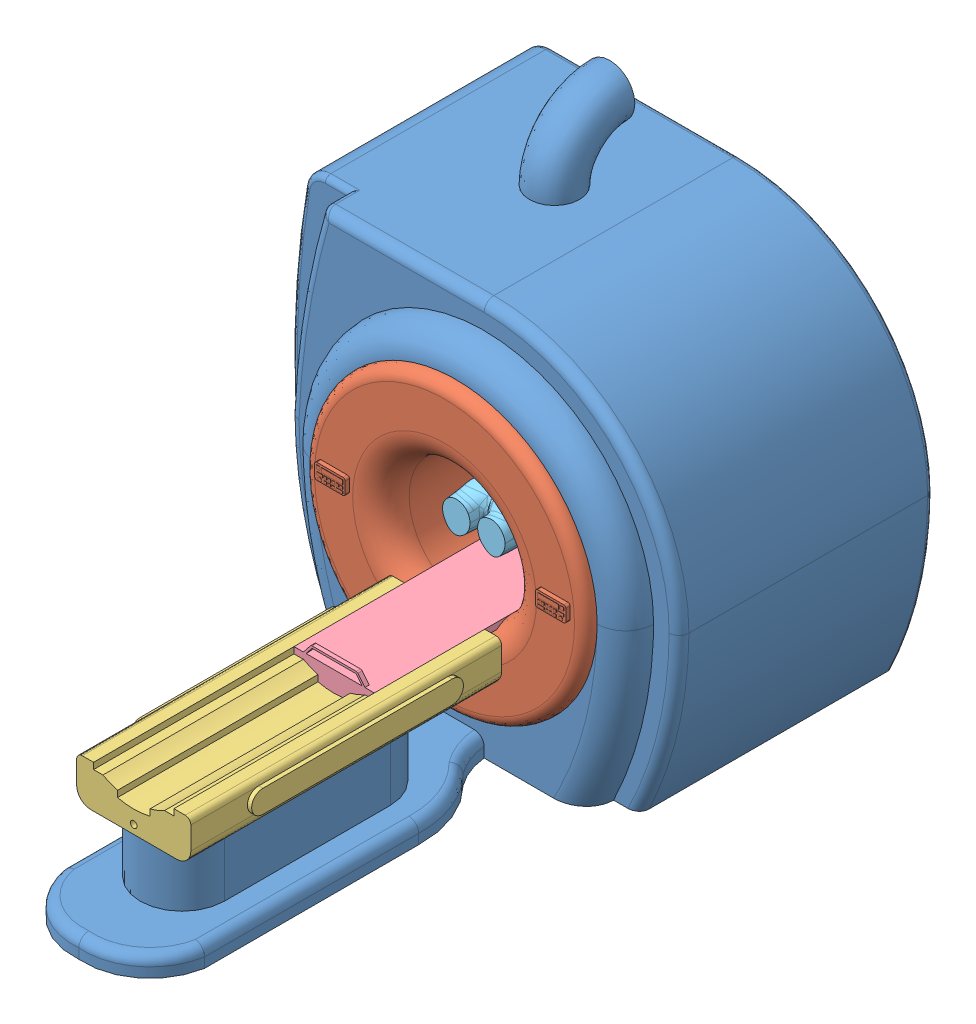
SolidWorks assembly Assem1, configuration Default. Lengths in mm.
Overall size (2298.25 2472.53 3646.55).
32 component instances, 9 part files, 5 mates.
Components (placement in the parent):
- MRI scanner-1: MRI scanner [Default] at (661.8458 1614.7998 1684.1916) size (2298.25 2472.53 3646.55)
  - Base Frame-1: Base Frame [Default] at (215.0742 187.8159 122.1083) size (2298.25 2472.53 3646.55)
  - Center Part-1: Center Part [Default] at (370.4063 184.7421 93.4615) size (1560 1560 1647.36)
  - Bed Base-1: Bed Base [Default] at (341.9747 -206.076 1751.6096) size (677.53 234 1716)
- Moving Bed-1: Moving Bed [Default] at (1003.8204 1488.5238 2331.8957) size (443.53 166.13 1716)
- BODYdetector-1: BODYdetector [Default] at (1333.5862 1343.5533 2745.5924) x (-1 0 0) z (0 0 -1) size (637.83 457.49 817.55)
  - woman body-1: woman body [Default] at (325.4407 484.4544 221.086) size (637.83 301.02 817.55)
  - Detector_posterial-1: Detector_posterial [Default] at (222.7152 725.2068 938.4124) x (1 0 0) z (0 0 -1) size (482.7 103.57 200)
    - 1Detector-1: 1Detector [Default] at (83.9721 85.3161 150.6758) size (71 32 200)
    - 1Detector-2: 1Detector [Default] at (152.9721 85.3161 150.6758) size (71 32 200)
    - 1Detector-3: 1Detector [Default] at (14.9721 85.3161 150.6758) size (71 32 200)
    - 1Detector-4: 1Detector [Default] at (-63.2042 99.8052 150.6758) x (0.93358 -0.358368 0) z (0 0 1) size (71 32 200)
    - 1Detector-5: 1Detector [Default] at (231.1484 99.8052 150.6758) x (0.93358 0.358368 0) z (0 0 1) size (71 32 200)
    - 1Detector_3modules-1: 1Detector_3modules [Default] at (-130.9957 141.3479 175.6758) x (0.743145 -0.669131 0) z (0 0 1) size (71 32 150)
    - 1Detector_3modules-2: 1Detector_3modules [Default] at (298.9398 141.3479 175.6758) x (0.743145 0.669131 0) z (0 0 1) size (71 32 150)
  - Detector1n2_2-1: Detector1n2_2 [Default] at (262.1834 410.9569 572.8392) x (1 0 0) z (0 -1 0) size (495.24 340.33 230.2)
    - top_bottomDetector2-1: top_bottomDetector2 [Default] at (5.3043 60.2155 74.3483) size (141 32 149.74)
    - CshapedDetector2-1: CshapedDetector2 [Default] at (104.3454 -76.5763 -85.899) x (0.951057 0.309017 0) z (0 0 1) size (177.89 270.84 200)
      - 1Detector-2: 1Detector [Default] at (173.0714 153.2337 184.2598) x (0.809017 0.587785 0) z (0 0 1) size (71 32 200)
      - 1Detector-4: 1Detector [Default] at (223.2683 222.3237 184.2598) x (0.309017 0.951057 0) z (0 0 1) size (71 32 200)
      - 1Detector-5: 1Detector [Default] at (223.2683 307.7237 184.2598) x (-0.309017 0.951057 0) z (0 0 1) size (71 32 200)
      - 1Detector_3modules-1: 1Detector_3modules [Default] at (91.8512 126.8436 209.2598) size (71 32 150)
      - 1Detector_3modules-2: 1Detector_3modules [Default] at (173.0714 376.8138 209.2598) x (-0.809017 0.587785 0) z (0 0 1) size (71 32 150)
    - CshapedDetector2-2: CshapedDetector2 [Default] at (-23.7368 484.2959 -85.899) x (-0.951057 -0.309017 0) z (0 0 1) size (177.89 270.84 200)
      - 1Detector-2: 1Detector [Default] at (173.0714 153.2337 184.2598) x (0.809017 0.587785 0) z (0 0 1) size (71 32 200)
      - 1Detector-4: 1Detector [Default] at (223.2683 222.3237 184.2598) x (0.309017 0.951057 0) z (0 0 1) size (71 32 200)
      - 1Detector-5: 1Detector [Default] at (223.2683 307.7237 184.2598) x (-0.309017 0.951057 0) z (0 0 1) size (71 32 200)
      - 1Detector_3modules-1: 1Detector_3modules [Default] at (91.8512 126.8436 209.2598) size (71 32 150)
      - 1Detector_3modules-2: 1Detector_3modules [Default] at (173.0714 376.8138 209.2598) x (-0.809017 0.587785 0) z (0 0 1) size (71 32 150)
    - top_bottomDetector2-2: top_bottomDetector2 [Default] at (75.3043 347.5042 74.3483) x (-1 0 0) z (0 0 1) size (141 32 149.74)
    - Detector2-1: Detector2 [Default] at (-50.3758 204.3598 228.5608) x (1 0 0) z (0 1 0) size (170 30.5 151.04)
    - Detector2-2: Detector2 [Default] at (130.9844 204.3598 228.5608) x (1 0 0) z (0 1 0) size (170 30.5 151.04)
Mates (geometry in assembly coordinates):
- Coincident1: coincident aligned: line of MRI scanner-1/Bed Base-1 through (810.4856 1491.0005 4405.104) axis (0 0 -1); line of Moving Bed-1 through (810.4856 1491.0005 3298.5256) axis (0 0 -1)
- Parallel1: parallel anti-aligned: plane of MRI scanner-1/Bed Base-1 through (810.4856 1491.0005 4405.104) normal (0 1 0); plane of Moving Bed-1 through (810.4856 1491.0005 3298.5256) normal (0 -1 0)
- Coincident4: coincident anti-aligned: plane of Moving Bed-1 through (810.4856 1525.9494 3298.5256) normal (0 1 0); plane of BODYdetector-1/Detector1n2_2-1/Detector2-2 through (940.4185 1525.9494 1968.3934) normal (0 -1 0)
- Distance2: distance = 228.6 mm: line of Moving Bed-1 through (1254.0185 1525.9494 3298.5256) axis (0 0 -1); line of BODYdetector-1/Detector1n2_2-1/Detector2-2 through (1025.4185 1525.9494 2043.3934) axis (0 0 -1)
- Distance3: distance = 310.8678 mm: line of BODYdetector-1/Detector1n2_2-1/Detector2-1 through (1206.7786 1525.9494 1893.3934) axis (-1 0 0); line of Moving Bed-1 through (1254.0185 1525.9494 1582.5256) axis (-1 0 0)
